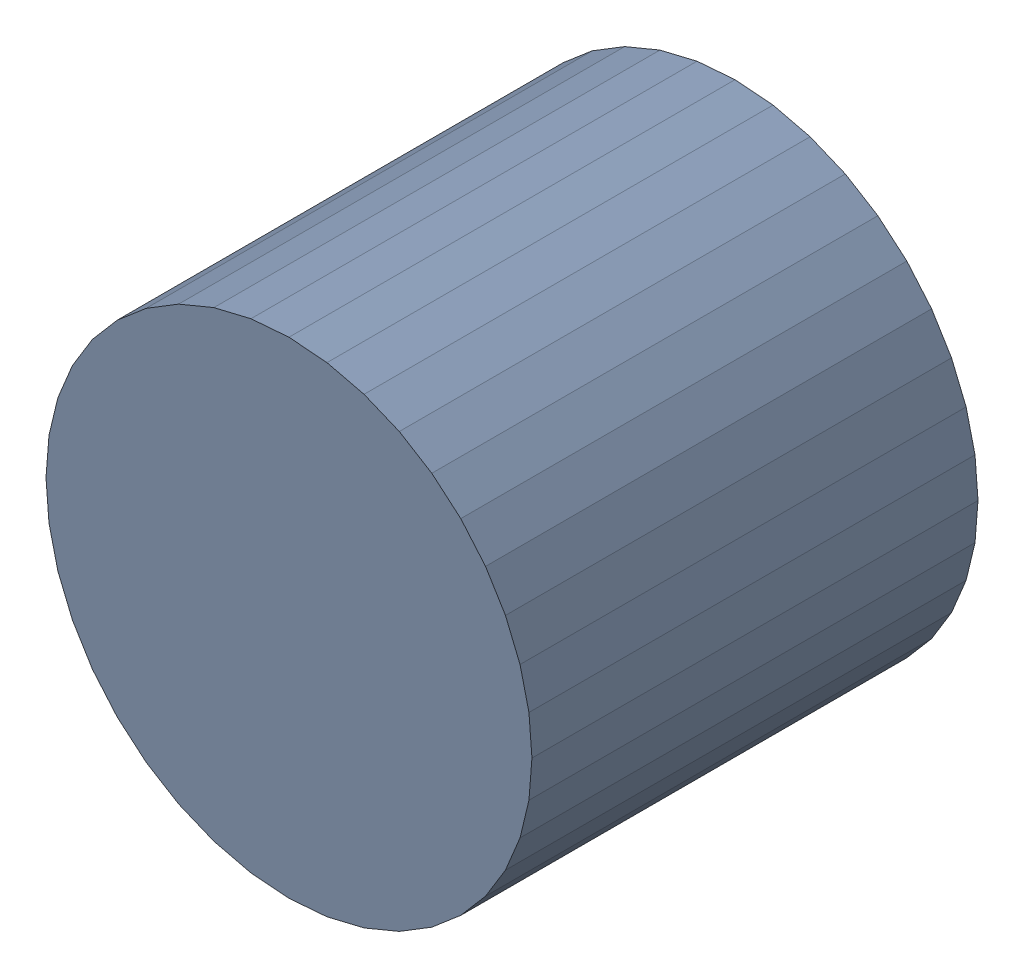
SolidWorks assembly USB23_C7, configuration Default. Lengths in mm.
Overall size (6.32 6.32 5.8).
2 component instances, 1 part files, 0 mates.
Components (placement in the parent):
- 384312384-1: 384312384 [Default] at (149.86 59.055 -6.9024) size (6.32 6.32 5.8)
  - Extruded_7-1: Extruded_7 [Default] at origin size (6.32 6.32 5.8)
